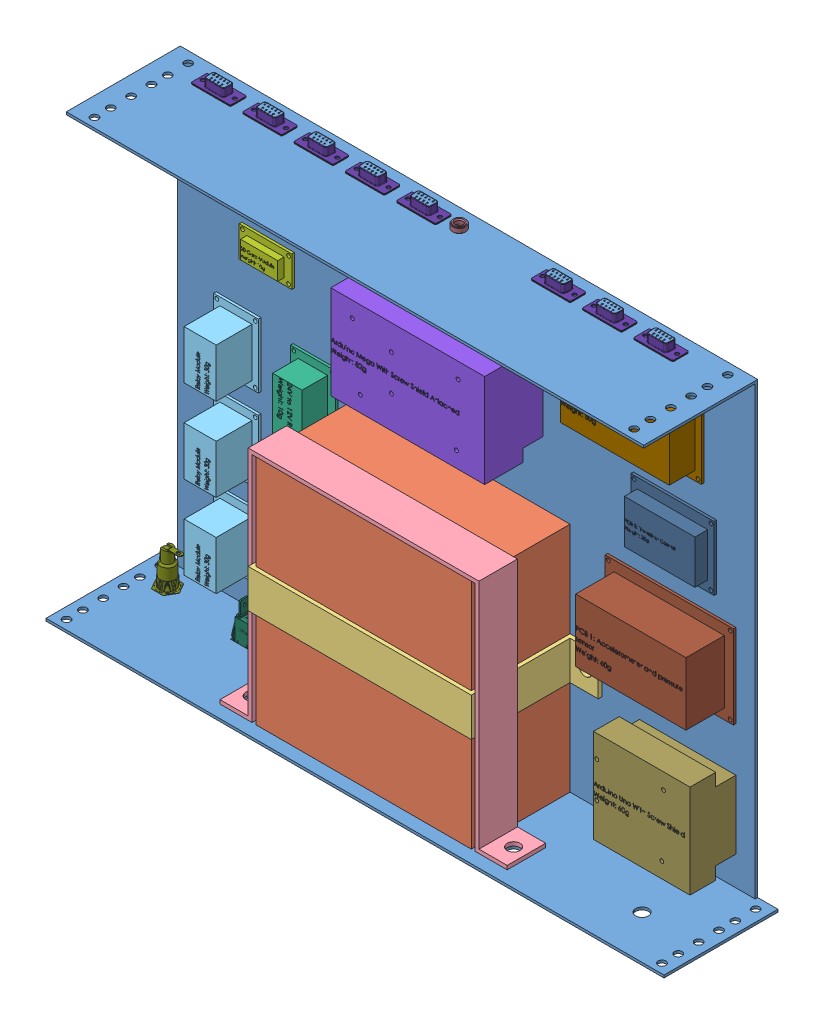
SolidWorks assembly Tray Final v2, configuration Default. Lengths in mm.
Overall size (482 368.35 88.9).
123 component instances, 20 part files, 49 mates.
Components (placement in the parent):
- Tray fix-1: Tray fix [Default] at (-140.6124 -26.842 47.9853) size (482 352 88.9)
- Battery-1: Battery [Default] at (-227.8124 -19.842 49.9853) size (168 181 77)
- Battery strap 77mm high-1: Battery strap 77mm high [Default] at (-143.8124 -123.842 49.9853) x (-1 0 0) z (0 1 0) size (218 80 30)
- Battery strap 181mm long-1: Battery strap 181mm long [Default] at (-143.8124 -200.842 96.9853) size (224 184 30)
- Relay Module V3-1: Relay Module V3 [Default] at (-318.3124 -155.842 49.9853) x (-1 0 0) z (0 1 0) size (35 30 50)
- Relay Module V3-2: Relay Module V3 [Default] at (-318.3124 -90.842 49.9853) x (-1 0 0) z (0 1 0) size (35 30 50)
- Relay Module V3-3: Relay Module V3 [Default] at (-318.3124 -25.842 49.9853) x (-1 0 0) z (0 1 0) size (35 30 50)
- 24 to 12V regulator-1: 24 to 12V regulator [Default] at (-258.3124 -38.342 49.9853) size (35 65 22)
- SD Card module-1: SD Card module [Default] at (-295.3124 44.158 49.9853) size (41 24 7)
- Arduino Mega with Screw Shield Attached-1: Arduino Mega with Screw Shield Attached [Default] at (-140.8124 55.658 49.9853) size (120 73 45.59)
- PCB 3 TTL TO RS485-1: PCB 3 TTL TO RS485 [Default] at (-2.9124 86.158 49.9853) size (95 52 22)
- PSB 2 Thermistor control-1: PSB 2 Thermistor control [Default] at (22.0876 15.158 49.9853) size (65 50 12)
- PCB 1 accelerometer and pressure sensor-1: PCB 1 accelerometer and pressure sensor [Default] at (19.5876 -57.342 49.9853) size (100 65 32)
- Arduino Uno with Screw shield-1: Arduino Uno with Screw shield [Default] at (31.9501 -151.342 49.9853) size (75.27 73 35.8)
- DC Jack Panel Mount ASSY-1: DC Jack Panel Mount ASSY [Default] at (-133.0964 153.458 63.1731) x (1 0 0) z (0 1 0) size (17.52 16.47 17.63)
  - DC Jack Panel Mount Base-1: DC Jack Panel Mount Base [Default] at origin size (10.2 10.2 17.63)
  - DC Jack Panel Mount Nut-1: DC Jack Panel Mount Nut [Default] at (0 0 -7.35) x (0.866025 -0.5 0) z (0 0 1) size (13.88 11 3.18)
- Rocker Switch Red LED-2: Rocker Switch Red LED [Default] at (-280.2124 -202.842 67.3853) x (0 0 -1) z (-1 0 0) size (25 38.05 31)
- Fuse-3: Fuse [Predeterminado] at (-355.7124 -174.295 67.9853) x (-1 0 0) z (0 0 1) size (20.79 34.8 18.38)
- D-tupe 9 pin female-1: D-tupe 9 pin female [Default] at (-334.4603 128.1098 80.5883) x (1 0 0) z (0 1 0) size (30.84 12.55 15.35)
  - D-type 2-1: D-type 2 [Default] at (13.8361 17.4152 21.5482) size (30.84 12.55 7.3)
  - D-type 1-1: D-type 1 [Default] at (13.8361 17.4152 21.5482) x (-1 0 0) z (0 0 -1) size (30.84 12.55 4.4)
  - D-type 3-1: D-type 3 [Default] at (13.8361 17.4152 17.6482) size (16.3 8.2 12.45)
  - D-type pin female-1: D-type pin female [Default] at (19.3761 18.8352 27.7482) x (-1 0 0) z (0 0 -1) size (1.6 1.6 14.86)
  - D-type pin female-2: D-type pin female [Default] at (16.6061 18.8352 27.7482) x (-1 0 0) z (0 0 -1) size (1.6 1.6 14.86)
  - D-type pin female-3: D-type pin female [Default] at (13.8361 18.8352 27.7482) x (-1 0 0) z (0 0 -1) size (1.6 1.6 14.86)
  - D-type pin female-4: D-type pin female [Default] at (11.0661 18.8352 27.7482) x (-1 0 0) z (0 0 -1) size (1.6 1.6 14.86)
  - D-type pin female-5: D-type pin female [Default] at (8.2961 18.8352 27.7482) x (-1 0 0) z (0 0 -1) size (1.6 1.6 14.86)
  - D-type pin female-6: D-type pin female [Default] at (9.6855 15.9952 27.7482) x (1 0 0) z (0 0 -1) size (1.6 1.6 14.86)
  - D-type pin female-7: D-type pin female [Default] at (12.4555 15.9952 27.7482) x (1 0 0) z (0 0 -1) size (1.6 1.6 14.86)
  - D-type pin female-8: D-type pin female [Default] at (17.9955 15.9952 27.7482) x (1 0 0) z (0 0 -1) size (1.6 1.6 14.86)
  - D-type pin female-9: D-type pin female [Default] at (15.2255 15.9952 27.7482) x (1 0 0) z (0 0 -1) size (1.6 1.6 14.86)
- D-tupe 9 pin female-9: D-tupe 9 pin female [Default] at (-294.4603 128.1098 80.5883) x (1 0 0) z (0 1 0) size (30.84 12.55 15.35)
  - D-type 2-1: D-type 2 [Default] at (13.8361 17.4152 21.5482) size (30.84 12.55 7.3)
  - D-type 1-1: D-type 1 [Default] at (13.8361 17.4152 21.5482) x (-1 0 0) z (0 0 -1) size (30.84 12.55 4.4)
  - D-type 3-1: D-type 3 [Default] at (13.8361 17.4152 17.6482) size (16.3 8.2 12.45)
  - D-type pin female-1: D-type pin female [Default] at (19.3761 18.8352 27.7482) x (-1 0 0) z (0 0 -1) size (1.6 1.6 14.86)
  - D-type pin female-2: D-type pin female [Default] at (16.6061 18.8352 27.7482) x (-1 0 0) z (0 0 -1) size (1.6 1.6 14.86)
  - D-type pin female-3: D-type pin female [Default] at (13.8361 18.8352 27.7482) x (-1 0 0) z (0 0 -1) size (1.6 1.6 14.86)
  - D-type pin female-4: D-type pin female [Default] at (11.0661 18.8352 27.7482) x (-1 0 0) z (0 0 -1) size (1.6 1.6 14.86)
  - D-type pin female-5: D-type pin female [Default] at (8.2961 18.8352 27.7482) x (-1 0 0) z (0 0 -1) size (1.6 1.6 14.86)
  - D-type pin female-6: D-type pin female [Default] at (9.6855 15.9952 27.7482) x (1 0 0) z (0 0 -1) size (1.6 1.6 14.86)
  - D-type pin female-7: D-type pin female [Default] at (12.4555 15.9952 27.7482) x (1 0 0) z (0 0 -1) size (1.6 1.6 14.86)
  - D-type pin female-8: D-type pin female [Default] at (17.9955 15.9952 27.7482) x (1 0 0) z (0 0 -1) size (1.6 1.6 14.86)
  - D-type pin female-9: D-type pin female [Default] at (15.2255 15.9952 27.7482) x (1 0 0) z (0 0 -1) size (1.6 1.6 14.86)
- D-tupe 9 pin female-10: D-tupe 9 pin female [Default] at (-254.4603 128.1098 80.5883) x (1 0 0) z (0 1 0) size (30.84 12.55 15.35)
  - D-type 2-1: D-type 2 [Default] at (13.8361 17.4152 21.5482) size (30.84 12.55 7.3)
  - D-type 1-1: D-type 1 [Default] at (13.8361 17.4152 21.5482) x (-1 0 0) z (0 0 -1) size (30.84 12.55 4.4)
  - D-type 3-1: D-type 3 [Default] at (13.8361 17.4152 17.6482) size (16.3 8.2 12.45)
  - D-type pin female-1: D-type pin female [Default] at (19.3761 18.8352 27.7482) x (-1 0 0) z (0 0 -1) size (1.6 1.6 14.86)
  - D-type pin female-2: D-type pin female [Default] at (16.6061 18.8352 27.7482) x (-1 0 0) z (0 0 -1) size (1.6 1.6 14.86)
  - D-type pin female-3: D-type pin female [Default] at (13.8361 18.8352 27.7482) x (-1 0 0) z (0 0 -1) size (1.6 1.6 14.86)
  - D-type pin female-4: D-type pin female [Default] at (11.0661 18.8352 27.7482) x (-1 0 0) z (0 0 -1) size (1.6 1.6 14.86)
  - D-type pin female-5: D-type pin female [Default] at (8.2961 18.8352 27.7482) x (-1 0 0) z (0 0 -1) size (1.6 1.6 14.86)
  - D-type pin female-6: D-type pin female [Default] at (9.6855 15.9952 27.7482) x (1 0 0) z (0 0 -1) size (1.6 1.6 14.86)
  - D-type pin female-7: D-type pin female [Default] at (12.4555 15.9952 27.7482) x (1 0 0) z (0 0 -1) size (1.6 1.6 14.86)
  - D-type pin female-8: D-type pin female [Default] at (17.9955 15.9952 27.7482) x (1 0 0) z (0 0 -1) size (1.6 1.6 14.86)
  - D-type pin female-9: D-type pin female [Default] at (15.2255 15.9952 27.7482) x (1 0 0) z (0 0 -1) size (1.6 1.6 14.86)
- D-tupe 9 pin female-11: D-tupe 9 pin female [Default] at (-214.4603 128.1098 80.5883) x (1 0 0) z (0 1 0) size (30.84 12.55 15.35)
  - D-type 2-1: D-type 2 [Default] at (13.8361 17.4152 21.5482) size (30.84 12.55 7.3)
  - D-type 1-1: D-type 1 [Default] at (13.8361 17.4152 21.5482) x (-1 0 0) z (0 0 -1) size (30.84 12.55 4.4)
  - D-type 3-1: D-type 3 [Default] at (13.8361 17.4152 17.6482) size (16.3 8.2 12.45)
  - D-type pin female-1: D-type pin female [Default] at (19.3761 18.8352 27.7482) x (-1 0 0) z (0 0 -1) size (1.6 1.6 14.86)
  - D-type pin female-2: D-type pin female [Default] at (16.6061 18.8352 27.7482) x (-1 0 0) z (0 0 -1) size (1.6 1.6 14.86)
  - D-type pin female-3: D-type pin female [Default] at (13.8361 18.8352 27.7482) x (-1 0 0) z (0 0 -1) size (1.6 1.6 14.86)
  - D-type pin female-4: D-type pin female [Default] at (11.0661 18.8352 27.7482) x (-1 0 0) z (0 0 -1) size (1.6 1.6 14.86)
  - D-type pin female-5: D-type pin female [Default] at (8.2961 18.8352 27.7482) x (-1 0 0) z (0 0 -1) size (1.6 1.6 14.86)
  - D-type pin female-6: D-type pin female [Default] at (9.6855 15.9952 27.7482) x (1 0 0) z (0 0 -1) size (1.6 1.6 14.86)
  - D-type pin female-7: D-type pin female [Default] at (12.4555 15.9952 27.7482) x (1 0 0) z (0 0 -1) size (1.6 1.6 14.86)
  - D-type pin female-8: D-type pin female [Default] at (17.9955 15.9952 27.7482) x (1 0 0) z (0 0 -1) size (1.6 1.6 14.86)
  - D-type pin female-9: D-type pin female [Default] at (15.2255 15.9952 27.7482) x (1 0 0) z (0 0 -1) size (1.6 1.6 14.86)
- D-tupe 9 pin female-12: D-tupe 9 pin female [Default] at (-174.4603 128.1098 80.5883) x (1 0 0) z (0 1 0) size (30.84 12.55 15.35)
  - D-type 2-1: D-type 2 [Default] at (13.8361 17.4152 21.5482) size (30.84 12.55 7.3)
  - D-type 1-1: D-type 1 [Default] at (13.8361 17.4152 21.5482) x (-1 0 0) z (0 0 -1) size (30.84 12.55 4.4)
  - D-type 3-1: D-type 3 [Default] at (13.8361 17.4152 17.6482) size (16.3 8.2 12.45)
  - D-type pin female-1: D-type pin female [Default] at (19.3761 18.8352 27.7482) x (-1 0 0) z (0 0 -1) size (1.6 1.6 14.86)
  - D-type pin female-2: D-type pin female [Default] at (16.6061 18.8352 27.7482) x (-1 0 0) z (0 0 -1) size (1.6 1.6 14.86)
  - D-type pin female-3: D-type pin female [Default] at (13.8361 18.8352 27.7482) x (-1 0 0) z (0 0 -1) size (1.6 1.6 14.86)
  - D-type pin female-4: D-type pin female [Default] at (11.0661 18.8352 27.7482) x (-1 0 0) z (0 0 -1) size (1.6 1.6 14.86)
  - D-type pin female-5: D-type pin female [Default] at (8.2961 18.8352 27.7482) x (-1 0 0) z (0 0 -1) size (1.6 1.6 14.86)
  - D-type pin female-6: D-type pin female [Default] at (9.6855 15.9952 27.7482) x (1 0 0) z (0 0 -1) size (1.6 1.6 14.86)
  - D-type pin female-7: D-type pin female [Default] at (12.4555 15.9952 27.7482) x (1 0 0) z (0 0 -1) size (1.6 1.6 14.86)
  - D-type pin female-8: D-type pin female [Default] at (17.9955 15.9952 27.7482) x (1 0 0) z (0 0 -1) size (1.6 1.6 14.86)
  - D-type pin female-9: D-type pin female [Default] at (15.2255 15.9952 27.7482) x (1 0 0) z (0 0 -1) size (1.6 1.6 14.86)
- D-tupe 9 pin female-13: D-tupe 9 pin female [Default] at (-69.4603 128.1098 80.5883) x (1 0 0) z (0 1 0) size (30.84 12.55 15.35)
  - D-type 2-1: D-type 2 [Default] at (13.8361 17.4152 21.5482) size (30.84 12.55 7.3)
  - D-type 1-1: D-type 1 [Default] at (13.8361 17.4152 21.5482) x (-1 0 0) z (0 0 -1) size (30.84 12.55 4.4)
  - D-type 3-1: D-type 3 [Default] at (13.8361 17.4152 17.6482) size (16.3 8.2 12.45)
  - D-type pin female-1: D-type pin female [Default] at (19.3761 18.8352 27.7482) x (-1 0 0) z (0 0 -1) size (1.6 1.6 14.86)
  - D-type pin female-2: D-type pin female [Default] at (16.6061 18.8352 27.7482) x (-1 0 0) z (0 0 -1) size (1.6 1.6 14.86)
  - D-type pin female-3: D-type pin female [Default] at (13.8361 18.8352 27.7482) x (-1 0 0) z (0 0 -1) size (1.6 1.6 14.86)
  - D-type pin female-4: D-type pin female [Default] at (11.0661 18.8352 27.7482) x (-1 0 0) z (0 0 -1) size (1.6 1.6 14.86)
  - D-type pin female-5: D-type pin female [Default] at (8.2961 18.8352 27.7482) x (-1 0 0) z (0 0 -1) size (1.6 1.6 14.86)
  - D-type pin female-6: D-type pin female [Default] at (9.6855 15.9952 27.7482) x (1 0 0) z (0 0 -1) size (1.6 1.6 14.86)
  - D-type pin female-7: D-type pin female [Default] at (12.4555 15.9952 27.7482) x (1 0 0) z (0 0 -1) size (1.6 1.6 14.86)
  - D-type pin female-8: D-type pin female [Default] at (17.9955 15.9952 27.7482) x (1 0 0) z (0 0 -1) size (1.6 1.6 14.86)
  - D-type pin female-9: D-type pin female [Default] at (15.2255 15.9952 27.7482) x (1 0 0) z (0 0 -1) size (1.6 1.6 14.86)
- D-tupe 9 pin female-14: D-tupe 9 pin female [Default] at (-29.4603 128.1098 80.5883) x (1 0 0) z (0 1 0) size (30.84 12.55 15.35)
  - D-type 2-1: D-type 2 [Default] at (13.8361 17.4152 21.5482) size (30.84 12.55 7.3)
  - D-type 1-1: D-type 1 [Default] at (13.8361 17.4152 21.5482) x (-1 0 0) z (0 0 -1) size (30.84 12.55 4.4)
  - D-type 3-1: D-type 3 [Default] at (13.8361 17.4152 17.6482) size (16.3 8.2 12.45)
  - D-type pin female-1: D-type pin female [Default] at (19.3761 18.8352 27.7482) x (-1 0 0) z (0 0 -1) size (1.6 1.6 14.86)
  - D-type pin female-2: D-type pin female [Default] at (16.6061 18.8352 27.7482) x (-1 0 0) z (0 0 -1) size (1.6 1.6 14.86)
  - D-type pin female-3: D-type pin female [Default] at (13.8361 18.8352 27.7482) x (-1 0 0) z (0 0 -1) size (1.6 1.6 14.86)
  - D-type pin female-4: D-type pin female [Default] at (11.0661 18.8352 27.7482) x (-1 0 0) z (0 0 -1) size (1.6 1.6 14.86)
  - D-type pin female-5: D-type pin female [Default] at (8.2961 18.8352 27.7482) x (-1 0 0) z (0 0 -1) size (1.6 1.6 14.86)
  - D-type pin female-6: D-type pin female [Default] at (9.6855 15.9952 27.7482) x (1 0 0) z (0 0 -1) size (1.6 1.6 14.86)
  - D-type pin female-7: D-type pin female [Default] at (12.4555 15.9952 27.7482) x (1 0 0) z (0 0 -1) size (1.6 1.6 14.86)
  - D-type pin female-8: D-type pin female [Default] at (17.9955 15.9952 27.7482) x (1 0 0) z (0 0 -1) size (1.6 1.6 14.86)
  - D-type pin female-9: D-type pin female [Default] at (15.2255 15.9952 27.7482) x (1 0 0) z (0 0 -1) size (1.6 1.6 14.86)
- D-tupe 9 pin female-15: D-tupe 9 pin female [Default] at (10.5397 128.1098 80.5883) x (1 0 0) z (0 1 0) size (30.84 12.55 15.35)
  - D-type 2-1: D-type 2 [Default] at (13.8361 17.4152 21.5482) size (30.84 12.55 7.3)
  - D-type 1-1: D-type 1 [Default] at (13.8361 17.4152 21.5482) x (-1 0 0) z (0 0 -1) size (30.84 12.55 4.4)
  - D-type 3-1: D-type 3 [Default] at (13.8361 17.4152 17.6482) size (16.3 8.2 12.45)
  - D-type pin female-1: D-type pin female [Default] at (19.3761 18.8352 27.7482) x (-1 0 0) z (0 0 -1) size (1.6 1.6 14.86)
  - D-type pin female-2: D-type pin female [Default] at (16.6061 18.8352 27.7482) x (-1 0 0) z (0 0 -1) size (1.6 1.6 14.86)
  - D-type pin female-3: D-type pin female [Default] at (13.8361 18.8352 27.7482) x (-1 0 0) z (0 0 -1) size (1.6 1.6 14.86)
  - D-type pin female-4: D-type pin female [Default] at (11.0661 18.8352 27.7482) x (-1 0 0) z (0 0 -1) size (1.6 1.6 14.86)
  - D-type pin female-5: D-type pin female [Default] at (8.2961 18.8352 27.7482) x (-1 0 0) z (0 0 -1) size (1.6 1.6 14.86)
  - D-type pin female-6: D-type pin female [Default] at (9.6855 15.9952 27.7482) x (1 0 0) z (0 0 -1) size (1.6 1.6 14.86)
  - D-type pin female-7: D-type pin female [Default] at (12.4555 15.9952 27.7482) x (1 0 0) z (0 0 -1) size (1.6 1.6 14.86)
  - D-type pin female-8: D-type pin female [Default] at (17.9955 15.9952 27.7482) x (1 0 0) z (0 0 -1) size (1.6 1.6 14.86)
  - D-type pin female-9: D-type pin female [Default] at (15.2255 15.9952 27.7482) x (1 0 0) z (0 0 -1) size (1.6 1.6 14.86)
Mates (geometry in assembly coordinates):
- Coincident1: coincident anti-aligned: plane of Tray fix-1 through (-140.6124 -26.842 49.9853) normal (0 0 1); plane of Battery-1 through (-227.8124 -19.842 49.9853) normal (0 0 -1)
- Coincident2: coincident anti-aligned: plane of Tray fix-1 through (-140.6124 -200.842 47.9853) normal (0 1 0); plane of Battery-1 through (-227.8124 -200.842 126.9853) normal (0 -1 0)
- Distance1: distance = 138 mm: line of Tray fix-1 through (-365.8124 147.158 49.9853) axis (0 -1 0); plane of Battery-1 through (-227.8124 -19.842 126.9853) normal (-1 0 0)
- Coincident6: coincident anti-aligned: plane of Battery-1 through (-227.8124 -19.842 126.9853) normal (0 0 1); plane of Battery strap 77mm high-1 through (-59.8124 -93.842 126.9853) normal (0 0 -1)
- Coincident7: coincident anti-aligned: plane of Battery-1 through (-227.8124 -19.842 126.9853) normal (-1 0 0); plane of Battery strap 77mm high-1 through (-227.8124 -93.842 126.9853) normal (1 0 0)
- Distance3: distance = 77 mm anti-aligned: plane of Battery strap 77mm high-1 through (-143.8124 -123.842 49.9853) normal (0 -1 0); plane of Tray fix-1 through (-140.6124 -200.842 47.9853) normal (0 1 0)
- Coincident15: coincident anti-aligned: plane of Tray fix-1 through (-140.6124 -200.842 47.9853) normal (0 1 0); plane of Battery strap 181mm long-1 through (-255.8124 -200.842 126.9853) normal (0 -1 0)
- Concentric4: concentric anti-aligned: cylinder of Tray fix-1 through (-245.8124 149.159 111.9853) axis (0 -1 0) radius 5; cylinder of Battery strap 181mm long-1 through (-245.8124 -227.842 111.9853) axis (0 1 0) radius 5
- Concentric5: concentric anti-aligned: cylinder of Tray fix-1 through (-41.8124 149.159 111.9853) axis (0 -1 0) radius 5; circle of Battery strap 181mm long-1
- Coincident20: coincident anti-aligned: plane of Tray fix-1 through (-140.6124 -26.842 49.9853) normal (0 0 1); plane of Relay Module V3-1 through (-318.3124 -155.842 49.9853) normal (0 0 -1)
- Concentric10: concentric anti-aligned: cylinder of Tray fix-1 through (-333.3124 -133.342 19.9853) axis (0 0 1) radius 1.5; cylinder of Relay Module V3-1 through (-333.3124 -133.342 51.9853) axis (0 0 -1) radius 1.5
- Concentric11: concentric anti-aligned: cylinder of Tray fix-1 through (-303.3124 -178.342 19.9853) axis (0 0 1) radius 1.5; cylinder of Relay Module V3-1 through (-303.3124 -178.342 51.9853) axis (0 0 -1) radius 1.5
- Coincident21: coincident anti-aligned: plane of Tray fix-1 through (-140.6124 -26.842 49.9853) normal (0 0 1); plane of Relay Module V3-2 through (-318.3124 -90.842 49.9853) normal (0 0 -1)
- Coincident22: coincident anti-aligned: plane of Tray fix-1 through (-140.6124 -26.842 49.9853) normal (0 0 1); plane of Relay Module V3-3 through (-318.3124 -25.842 49.9853) normal (0 0 -1)
- Concentric12: concentric anti-aligned: cylinder of Tray fix-1 through (-333.3124 -113.342 19.9853) axis (0 0 1) radius 1.5; cylinder of Relay Module V3-2 through (-333.3124 -113.342 51.9853) axis (0 0 -1) radius 1.5
- Concentric13: concentric anti-aligned: cylinder of Tray fix-1 through (-333.3124 -48.342 19.9853) axis (0 0 1) radius 1.5; cylinder of Relay Module V3-3 through (-333.3124 -48.342 51.9853) axis (0 0 -1) radius 1.5
- Concentric14: concentric anti-aligned: cylinder of Tray fix-1 through (-303.3124 -68.342 19.9853) axis (0 0 1) radius 1.5; cylinder of Relay Module V3-2 through (-303.3124 -68.342 51.9853) axis (0 0 -1) radius 1.5
- Concentric15: concentric anti-aligned: cylinder of Tray fix-1 through (-303.3124 -3.342 19.9853) axis (0 0 1) radius 1.5; cylinder of Relay Module V3-3 through (-303.3124 -3.342 51.9853) axis (0 0 -1) radius 1.5
- Coincident23: coincident anti-aligned: plane of Tray fix-1 through (-140.6124 -26.842 49.9853) normal (0 0 1); plane of 24 to 12V regulator-1 through (-258.3124 -38.342 49.9853) normal (0 0 -1)
- Concentric16: concentric anti-aligned: cylinder of Tray fix-1 through (-243.3124 -68.342 19.9853) axis (0 0 1) radius 1.5; cylinder of 24 to 12V regulator-1 through (-243.3124 -68.342 51.9853) axis (0 0 -1) radius 1.5
- Concentric17: concentric anti-aligned: cylinder of Tray fix-1 through (-273.3124 -8.342 19.9853) axis (0 0 1) radius 1.5; cylinder of 24 to 12V regulator-1 through (-273.3124 -8.342 51.9853) axis (0 0 -1) radius 1.5
- Coincident24: coincident anti-aligned: plane of Tray fix-1 through (-140.6124 -26.842 49.9853) normal (0 0 1); plane of SD Card module-1 through (-295.3124 44.158 49.9853) normal (0 0 -1)
- Coincident25: coincident anti-aligned: circle of Tray fix-1; cylinder of SD Card module-1 through (-313.3124 34.658 51.9853) axis (0 0 -1) radius 1.5
- Concentric18: concentric anti-aligned: cylinder of Tray fix-1 through (-277.3124 53.658 47.9843) axis (0 0 1) radius 1.5; cylinder of SD Card module-1 through (-277.3124 53.658 51.9853) axis (0 0 -1) radius 1.5
- Concentric19: concentric anti-aligned: cylinder of Tray fix-1 through (-184.0104 79.919 47.9843) axis (0 0 1) radius 1.5; cylinder of Arduino Mega with Screw Shield Attached-1 through (-184.0104 79.919 65.5753) axis (0 0 -1) radius 1.5
- Concentric20: concentric anti-aligned: cylinder of Tray fix-1 through (-153.5624 72.302 47.9843) axis (0 0 1) radius 1.5; cylinder of Arduino Mega with Screw Shield Attached-1 through (-153.5624 72.302 65.5753) axis (0 0 -1) radius 1.5
- Coincident26: coincident anti-aligned: plane of Tray fix-1 through (-140.6124 -26.842 49.9853) normal (0 0 1); plane of Arduino Mega with Screw Shield Attached-1 through (-140.8124 55.658 49.9853) normal (0 0 -1)
- Coincident27: coincident anti-aligned: plane of Tray fix-1 through (-140.6124 -26.842 49.9853) normal (0 0 1); plane of PCB 3 TTL TO RS485-1 through (-2.9124 86.158 49.9853) normal (0 0 -1)
- Concentric21: concentric anti-aligned: cylinder of Tray fix-1 through (42.0876 109.658 47.9843) axis (0 0 1) radius 1.5; cylinder of PCB 3 TTL TO RS485-1 through (42.0876 109.658 51.9853) axis (0 0 -1) radius 1.5
- Concentric22: concentric anti-aligned: cylinder of Tray fix-1 through (-47.9124 62.658 47.9843) axis (0 0 1) radius 1.5; cylinder of PCB 3 TTL TO RS485-1 through (-47.9124 62.658 51.9853) axis (0 0 -1) radius 1.5
- Concentric23: concentric anti-aligned: cylinder of Tray fix-1 through (-7.9124 37.658 47.9843) axis (0 0 1) radius 1.5; cylinder of PSB 2 Thermistor control-1 through (-7.9124 37.658 51.9853) axis (0 0 -1) radius 1.5
- Concentric24: concentric anti-aligned: cylinder of Tray fix-1 through (52.0876 -7.342 47.9843) axis (0 0 1) radius 1.5; cylinder of PSB 2 Thermistor control-1 through (52.0876 -7.342 51.9853) axis (0 0 -1) radius 1.5
- Concentric25: concentric anti-aligned: cylinder of Tray fix-1 through (67.0876 -27.342 47.9843) axis (0 0 1) radius 1.5; cylinder of PCB 1 accelerometer and pressure sensor-1 through (67.0876 -27.342 51.9853) axis (0 0 -1) radius 1.5
- Coincident28: coincident aligned: cylinder of Tray fix-1 through (-27.9124 -87.342 47.9843) axis (0 0 1) radius 1.5; circle of PCB 1 accelerometer and pressure sensor-1
- Coincident29: coincident anti-aligned: plane of Tray fix-1 through (-140.6124 -26.842 49.9853) normal (0 0 1); plane of PSB 2 Thermistor control-1 through (22.0876 15.158 49.9853) normal (0 0 -1)
- Coincident30: coincident anti-aligned: plane of Tray fix-1 through (-140.6124 -26.842 49.9853) normal (0 0 1); plane of PCB 1 accelerometer and pressure sensor-1 through (19.5876 -57.342 49.9853) normal (0 0 -1)
- Concentric26: concentric anti-aligned: cylinder of Tray fix-1 through (47.6026 -175.753 47.9843) axis (0 0 1) radius 1.5; cylinder of Arduino Uno with Screw shield-1 through (47.6026 -175.753 65.7853) axis (0 0 -1) radius 1.5
- Concentric27: concentric anti-aligned: cylinder of Tray fix-1 through (-3.1624 -132.309 47.9843) axis (0 0 1) radius 1.5; cylinder of Arduino Uno with Screw shield-1 through (-3.1624 -132.309 65.7853) axis (0 0 -1) radius 1.5
- Coincident31: coincident anti-aligned: plane of Tray fix-1 through (-140.6124 -26.842 49.9853) normal (0 0 1); plane of Arduino Uno with Screw shield-1 through (31.9501 -151.342 49.9853) normal (0 0 -1)
- Coincident32: coincident anti-aligned: plane of Tray fix-1 through (-140.6124 147.158 47.9853) normal (0 -1 0); plane of DC Jack Panel Mount ASSY-1/DC Jack Panel Mount Nut-1 through (-133.0964 147.158 63.1731) normal (0 1 0)
- Concentric28: concentric anti-aligned: circle of Tray fix-1; circle of DC Jack Panel Mount ASSY-1/DC Jack Panel Mount Base-1
- Coincident66: coincident anti-aligned: plane of Tray fix-1 through (-365.8124 -202.842 49.9853) normal (0 -1 0); plane of Rocker Switch Red LED-2 through (-280.2124 -202.842 67.3853) normal (0 1 0)
- Coincident69: coincident anti-aligned: plane of Tray fix-1 through (-295.7124 149.159 79.0853) normal (1 0 0); plane of Rocker Switch Red LED-2 through (-295.7124 -198.342 78.0853) normal (-1 0 0)
- Distance5: distance = 2 mm anti-aligned: plane of Rocker Switch Red LED-2 through (-264.9624 -204.942 54.8853) normal (0 0 -1); plane of Tray fix-1 through (-295.7124 149.159 56.8853) normal (0 0 1)
- Coincident73: coincident: plane of Tray fix-1 through (-365.8124 -202.842 49.9853) normal (0 -1 0); plane of Fuse-3 through (-355.7124 -202.842 67.9853) normal (0 1 0)
- Concentric49: concentric aligned: cylinder of Tray fix-1 through (-355.7124 149.159 67.9853) axis (0 -1 0) radius 4; cylinder of Fuse-3 through (-355.7124 -202.842 67.9853) axis (0 -1 0) radius 7.5
- Coincident75: coincident anti-aligned: plane of Tray fix-1 through (-365.8124 149.158 49.9853) normal (0 1 0); plane of D-tupe 9 pin female-1/D-type 1-1 through (-335.0442 149.158 57.8981) normal (0 -1 0)
- Concentric53: concentric aligned: cylinder of Tray fix-1 through (-333.1192 -202.843 63.1731) axis (0 1 0) radius 1.5; cylinder of D-tupe 9 pin female-1/D-type 2-1 through (-333.1192 145.3447 63.1731) axis (0 1 0) radius 1.525
- Parallel4: parallel aligned: line of D-tupe 9 pin female-1/D-type 2-1 through (-306.2042 150.158 56.8981) axis (-1 0 0); plane of Tray fix-1 through (-365.8124 149.158 49.9853) normal (0 1 0)
